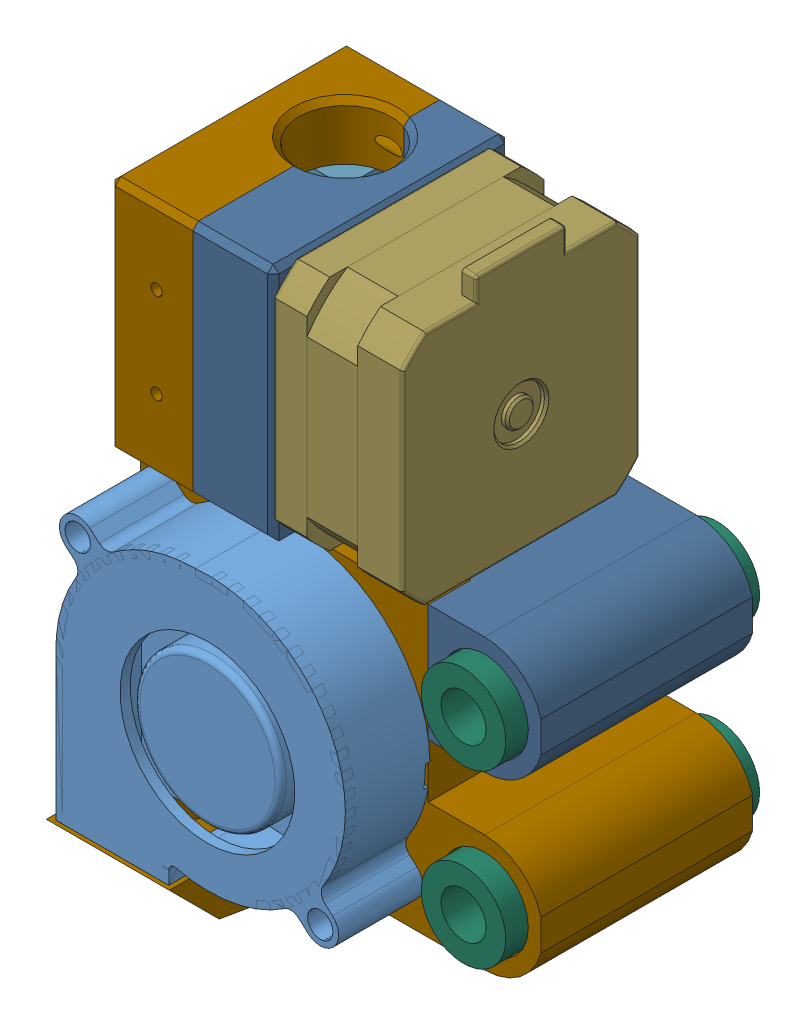
SolidWorks assembly Extruder, configuration Default. Lengths in mm.
Overall size (82.8 112.6 60.72).
19 component instances, 15 part files, 33 mates.
Components (placement in the parent):
- Extruder fan-1: Extruder fan [Default] at origin size (51.32 51.11 15)
  - CoverBottom^Extruder fan-1: CoverBottom^Extruder fan [Default] at origin size (51.32 51.11 15) (virtual)
- E3D-1: E3D [Default] at (-15.65 6.8806 -22.5) size (28.67 62.35 25.33)
  - E3D Heat Block-1: E3D Heat Block [Default] at origin size (20 12 16)
  - E3D Heatbreak-1: E3D Heatbreak [Default] at (-6 19.55 0) x (-0.93266 0 -0.360757) z (-0.360757 0 0.93266) size (6 25.1 6)
  - E3D Nozzle-1: E3D Nozzle [Default] at (-6 -3.5 0) x (-0.097107 0 -0.995274) z (0.995274 0 -0.097107) size (9.24 12.5 8)
  - E3D Heatsink-1: E3D Heatsink [1.75 Bowden] at (-6 35.475 0) x (0.986263 0 -0.165183) z (0.165183 0 0.986263) size (22 42.75 22)
  - cartridge heater-1: cartridge heater [Default] at (1 7 0) x (0 0 1) z (-0.150948 -0.988542 0) size (32 6.2 6.2)
  - thermistor-1: thermistor [Default] at (-8 2 6.5) x (-0.997586 0.069447 0) z (-0.069447 -0.997586 0) size (2 13.25 2)
- 30mm fan-1: 30mm fan [Default] at (-46.74 31.8556 -22.5) x (0 0 -1) z (1 0 0) size (30 30 10.44)
  - Component1.step-1: Component1.step [Default] at origin size (30 30 10.44)
- Fan shroud-1: Fan shroud [Default] at (-36.4 16.8556 -37.5) x (0 0 1) z (-1 0 0) size (53.2 105.2 72)
- Extruder-1: Extruder [Default] at (-7.4 59.9806 -7.5) x (0 0 -1) z (1 0 0) size (42 62.75 57.81)
- Extruder drive gear-1: Extruder drive gear [Default] at (-21.65 88.9806 -16.5) x (-1 0 0) z (0 0.036827 -0.999322) size (11 12 12.01)
- Extruder stepper-1: Extruder stepper [NEMA 17 L34] at (-7.4 88.9806 -16.5) x (0 0 -1) z (1 0 0) size (42 46 47)
- Filament bearing-1: Filament bearing [Default] at (-21.6656 90.7306 -31.838) x (0 -0.139313 -0.990248) z (0 -0.990248 0.139313) size (15.88 3.97 15.88)
- Bearing holder-1: Bearing holder [Default] at (-16.0563 77.7306 -45.0225) x (0 0 1) z (0 -1 0) size (20 16 22)
- Slide bearing-1: Slide bearing [Default] at (25.6 27.2306 3.75) x (-0.926759 -0.375657 0) z (0.375657 -0.926759 0) size (15 45 15)
- Slide bearing-2: Slide bearing [Default] at (25.6 57.6056 3.75) x (-0.813252 0.581911 0) z (-0.581911 -0.813252 0) size (15 45 15)
Mates (geometry in assembly coordinates):
- Parallel1: parallel anti-aligned: plane of Extruder fan-1/CoverBottom^Extruder fan-1 through (-9.7576 42.4117 0) normal (0 0 -1); plane of E3D-1/E3D Heat Block-1 through (-25.65 18.8806 -14.5) normal (0 0 1)
- Coincident2: coincident anti-aligned: plane of Fan shroud-1 through (-36.4 40.1056 -37.5) normal (-1 0 0); plane of 30mm fan-1/Component1.step-1 through (-36.4 31.8556 -22.5) normal (1 0 0)
- Coincident6: coincident: plane of Fan shroud-1 through (-36.4 40.1056 -37.5) normal (0 0 -1); line of 30mm fan-1/Component1.step-1 through (-36.4 18.4556 -37.5) axis (0 1 0)
- Parallel3: parallel aligned: plane of E3D-1/E3D Heat Block-1 through (-25.65 18.8806 -14.5) normal (-1 0 0); plane of Fan shroud-1 through (-36.4 40.1056 -37.5) normal (-1 0 0)
- Parallel4: parallel aligned: line of Extruder fan-1/CoverBottom^Extruder fan-1 through (20 -35.4 16.8556) axis (0 1 0); line of E3D-1/E3D Heat Block-1 through (-25.15 18.8806 -15) axis (1 0 0)
- Coincident13: coincident anti-aligned: plane of E3D-1/E3D Heatsink-1 through (-15.7324 59.9806 -23.4911) normal (0 -1 0); plane of Fan shroud-1 through (-21.65 59.9806 -22.5) normal (0 1 0)
- Concentric1: concentric aligned: circle of E3D-1/E3D Heatsink-1; circle of Fan shroud-1
- Coincident15: coincident anti-aligned: plane of Extruder fan-1/CoverBottom^Extruder fan-1 through (-9.7576 42.4117 0) normal (0 0 -1); plane of Fan shroud-1 through (-36.4 16.8556 0) normal (0 0 1)
- Coincident16: coincident aligned: line of Extruder fan-1/CoverBottom^Extruder fan-1 through (20 -35.4 16.8556) axis (0 1 0); line of Fan shroud-1 through (-14.6 16.8556 0) axis (1 0 0)
- Distance1: distance = 1 mm aligned: plane of Extruder fan-1/CoverBottom^Extruder fan-1 through (-35.4 42.2556 0) normal (-1 0 0); plane of Fan shroud-1 through (-36.4 40.1056 -37.5) normal (-1 0 0)
- Coincident18: coincident anti-aligned: plane of Fan shroud-1 through (-21.65 54.2306 -30.75) normal (1 0 0); plane of Extruder-1 through (-21.65 80.9806 -30.625) normal (-1 0 0)
- Concentric3: concentric aligned: circle of Extruder drive gear-1; circle of Extruder stepper-1
- Parallel5: parallel anti-aligned: plane of Extruder-1 through (-7.4 80.9806 -7.5) normal (1 0 0); plane of Extruder stepper-1 through (-7.4 88.9806 -16.5) normal (-1 0 0)
- Coincident20: coincident aligned: plane of Fan shroud-1 through (15.6 67.9806 0) normal (1 0 0); plane of Extruder stepper-1 through (15.6 88.9806 -16.5) normal (1 0 0)
- Coincident23: coincident aligned: plane of Extruder-1 through (-7.4 80.9806 -37.5) normal (0 0 -1); plane of Extruder stepper-1 through (-1.4 105.9512 -37.5) normal (0 0 -1)
- Distance2: distance = 3 mm: cylinder of E3D-1/E3D Heatsink-1 through (-21.65 20.9806 -22.5) axis (0 -1 0) radius 2; plane of Extruder drive gear-1 through (-24.65 88.9806 -16.5) normal (-1 0 0)
- Parallel6: parallel anti-aligned: plane of Extruder stepper-1 through (-7.4 88.9806 -16.5) normal (-1 0 0); plane of Filament bearing-1 through (-19.6813 90.7306 -31.838) normal (1 0 0)
- Distance3: distance = 1.5 mm: cylinder of Filament bearing-1 through (-19.6813 90.7306 -31.838) axis (-1 0 0) radius 7.9375; cylinder of Extruder drive gear-1 through (-24.65 88.9806 -16.5) axis (1 0 0) radius 6
- Distance4: distance = 1 mm aligned: plane of Filament bearing-1 through (-23.65 90.7306 -31.838) normal (-1 0 0); plane of Extruder drive gear-1 through (-24.65 88.9806 -16.5) normal (-1 0 0)
- Coincident26: coincident anti-aligned: plane of Fan shroud-1 through (-36.4 47.2306 -37.5) normal (0 1 0); plane of Extruder-1 through (-21.65 47.2306 -22.5) normal (0 -1 0)
- Coincident27: coincident anti-aligned: plane of Fan shroud-1 through (-21.65 67.9806 -22.5) normal (0 1 0); plane of Extruder stepper-1 through (15.6 67.9806 0.4706) normal (0 -1 0)
- Parallel8: parallel anti-aligned: plane of Extruder-1 through (-11.4 77.4806 -22.5) normal (-1 0 0); plane of Bearing holder-1 through (-16.0563 77.7306 -45.0225) normal (1 0 0)
- Parallel9: parallel anti-aligned: plane of Bearing holder-1 through (-32.0562 77.7306 -45.0225) normal (0 -1 0); plane of Extruder-1 through (-18.8778 77.4806 -22.5) normal (0 1 0)
- Concentric6: concentric aligned: cylinder of Filament bearing-1 through (-19.6813 90.7306 -31.838) axis (-1 0 0) radius 4.7625; circle of Bearing holder-1
- Coincident33: coincident anti-aligned: plane of Filament bearing-1 through (-19.6813 90.7306 -31.838) normal (1 0 0); plane of Bearing holder-1 through (-19.6813 90.7306 -31.838) normal (-1 0 0)
- Concentric7: concentric anti-aligned: circle of E3D-1/E3D Heatsink-1; circle of Extruder-1
- Width3: width anti-aligned: plane of Bearing holder-1 through (-32.0562 99.7306 -45.0225) normal (0 1 0); plane of Bearing holder-1 through (-32.0562 77.7306 -45.0225) normal (0 -1 0); plane of Extruder-1 through (-18.8778 99.9806 -22.5) normal (0 -1 0); plane of Extruder-1 through (-18.8778 77.4806 -22.5) normal (0 1 0)
- Coincident34: coincident aligned: plane of Slide bearing-1 through (25.6 27.2306 -41.25) normal (0 0 -1); plane of Slide bearing-2 through (25.6 57.6056 -41.25) normal (0 0 -1)
- Parallel10: parallel aligned: plane of Fan shroud-1 through (-36.4 40.1056 -37.5) normal (0 0 -1); plane of Slide bearing-1 through (25.6 27.2306 -41.25) normal (0 0 -1)
- Width4: width anti-aligned: plane of Slide bearing-2 through (25.6 57.6056 -41.25) normal (0 0 -1); plane of Slide bearing-2 through (25.6 57.6056 3.75) normal (0 0 1); plane of Fan shroud-1 through (-36.4 16.8556 0) normal (0 0 1); plane of Extruder-1 through (-7.4 80.9806 -37.5) normal (0 0 -1)
- Concentric8: concentric aligned: circle of Extruder-1; circle of Slide bearing-2
- Concentric9: concentric aligned: circle of Fan shroud-1; circle of Slide bearing-1
- Coincident35: coincident: line of 30mm fan-1/Component1.step-1 through (-36.4 16.8556 -9.1) axis (0 0 -1); plane of Fan shroud-1 through (-36.4 16.8556 -37.5) normal (0 -1 0)
